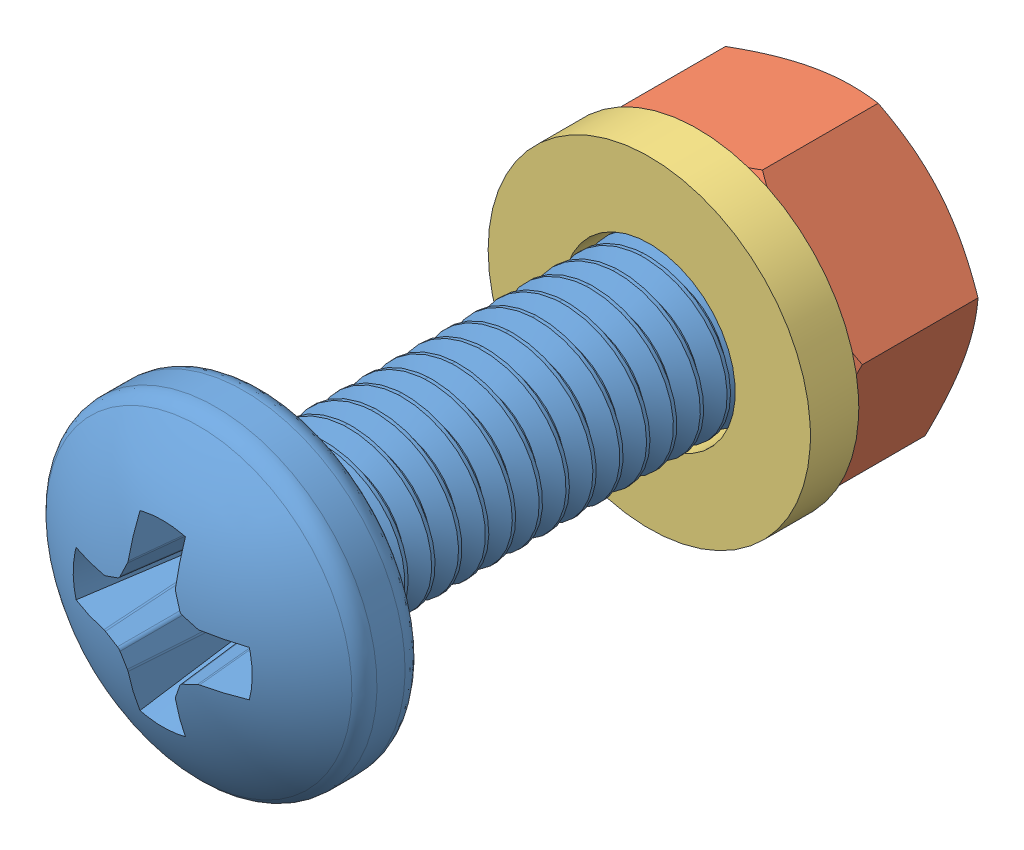
SolidWorks assembly M6 Screw Assy, configuration Default. Lengths in mm.
Overall size (13.12 12 26.01).
3 component instances, 3 part files, 5 mates.
Components (placement in the parent):
- M6 x 20mm Screw-1: M6 x 20mm Screw [90234A367] at origin size (12 12 24.48)
- M6 Nut-1: M6 Nut [91927A115] at (0 0 1.31) x (0.174956 -0.984576 0) z (0 0 1) size (10 11.55 5.91)
- M6 Washer-1: M6 Washer [98269A450] at (0 0 3.91) size (12 12 1.8)
Mates (geometry in assembly coordinates):
- Concentric1: concentric: circle of M6 x 20mm Screw-1; circle of M6 Washer-1
- Coincident1: coincident: line of M6 x 20mm Screw-1 through (0 0 -3.6938) axis (0 0 1); line of M6 Nut-1 through (0 0 -17.2242) axis (0 0 1)
- Screw1: screw = 1: line of M6 x 20mm Screw-1 through (0 0 -3.6938) axis (0 0 1); line of M6 Nut-1 through (0 0 -17.2242) axis (0 0 1)
- Coincident2: coincident: plane of M6 Nut-1 through (5.6011 -1.4002 -11.3236) normal (0 0 1); plane of M6 Washer-1 through (0 0 -11.3236) normal (0 0 -1)
- Distance1: distance = 14.29 mm: plane of M6 x 20mm Screw-1 through (0 0 20) normal (0 0 -1); plane of M6 Washer-1 through (0 0 5.71) normal (0 0 1)
